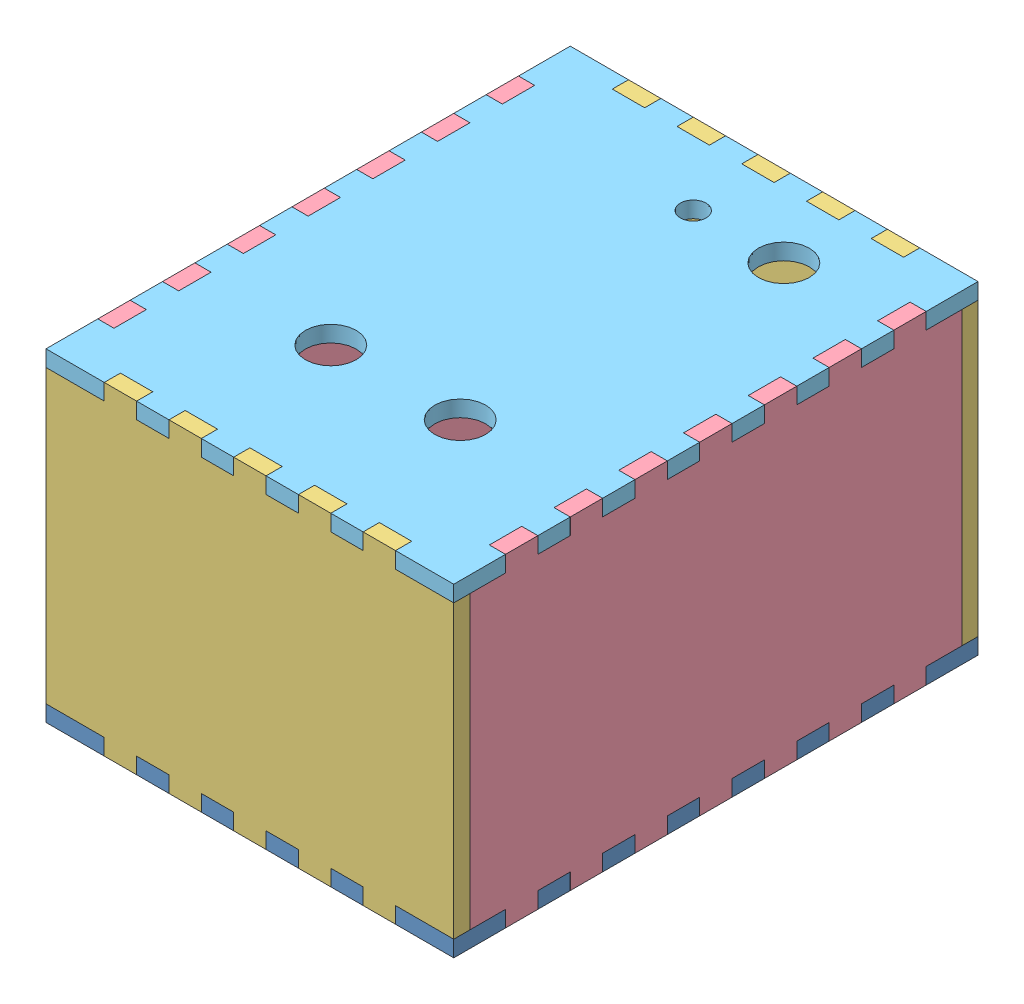
SolidWorks assembly ShellWithBreadboardAssy, configuration Default. Lengths in mm.
Overall size (80.01 63.5 102.87).
7 component instances, 5 part files, 18 mates.
Components (placement in the parent):
- ShellBottom-1: ShellBottom [Default] at (32.5711 51.104 75.4126) size (80.01 3.17 102.87)
- Breadboard-1: Breadboard [Default] at (32.5711 54.279 75.4126) x (0 0 1) z (-1 0 0) size (69 8.38 54)
- ShellShortSide-1: ShellShortSide [Default] at (32.5711 82.854 126.8476) x (0 0 -1) z (1 0 0) size (3.17 63.5 80.01)
- ShellShortSide-2: ShellShortSide [Battery cut-out] at (32.5711 82.854 27.1526) x (0 0 -1) z (1 0 0) size (3.17 63.5 80.01)
- ShellLongSide-1: ShellLongSide [Default] at (69.4011 82.854 75.4126) x (0 0 -1) z (1 0 0) size (96.52 63.5 3.17)
- ShellLongSide-2: ShellLongSide [Battery Mount Holes] at (-7.4339 82.854 75.4126) x (0 0 -1) z (1 0 0) size (96.52 63.5 3.17)
- ShellTop-1: ShellTop [Default] at (32.5711 111.429 75.4126) size (80.01 3.17 102.87)
Mates (geometry in assembly coordinates):
- Coincident1: coincident anti-aligned: plane of ShellBottom-1 through (32.5711 54.279 75.4126) normal (0 1 0); plane of Breadboard-1 through (32.5711 54.279 75.4126) normal (0 -1 0)
- Width1: width anti-aligned: plane of ShellBottom-1 through (-7.4339 54.279 126.8476) normal (0 0 1); plane of ShellBottom-1 through (-7.4339 54.279 23.9776) normal (0 0 -1); plane of Breadboard-1 through (59.5711 62.661 40.9126) normal (0 0 -1); plane of Breadboard-1 through (59.5711 62.661 109.9126) normal (0 0 1)
- Width2: width anti-aligned: plane of ShellBottom-1 through (72.5761 54.279 23.9776) normal (1 0 0); plane of ShellBottom-1 through (-7.4339 54.279 23.9776) normal (-1 0 0); plane of Breadboard-1 through (5.5711 62.661 40.9126) normal (-1 0 0); plane of Breadboard-1 through (59.5711 62.661 40.9126) normal (1 0 0)
- Coincident9: coincident aligned: plane of ShellBottom-1 through (32.5711 51.104 75.4126) normal (0 -1 0); plane of ShellShortSide-1 through (72.5761 51.104 123.6726) normal (0 -1 0)
- Coincident10: coincident aligned: plane of ShellBottom-1 through (72.5761 54.279 23.9776) normal (1 0 0); plane of ShellShortSide-1 through (72.5761 114.604 123.6726) normal (1 0 0)
- Coincident12: coincident aligned: plane of ShellBottom-1 through (32.5711 51.104 75.4126) normal (0 -1 0); plane of ShellShortSide-2 through (72.5761 51.104 23.9776) normal (0 -1 0)
- Coincident13: coincident aligned: plane of ShellBottom-1 through (-7.4339 54.279 23.9776) normal (-1 0 0); plane of ShellShortSide-2 through (-7.4339 114.604 23.9776) normal (-1 0 0)
- Coincident15: coincident aligned: plane of ShellBottom-1 through (32.5711 51.104 75.4126) normal (0 -1 0); plane of ShellLongSide-1 through (72.5761 51.104 123.6726) normal (0 -1 0)
- Coincident16: coincident anti-aligned: plane of ShellShortSide-1 through (32.5711 82.854 123.6726) normal (0 0 -1); plane of ShellLongSide-1 through (72.5761 114.604 123.6726) normal (0 0 1)
- Coincident18: coincident anti-aligned: plane of ShellShortSide-1 through (32.5711 82.854 123.6726) normal (0 0 -1); plane of ShellLongSide-2 through (-4.2589 114.604 123.6726) normal (0 0 1)
- Coincident19: coincident aligned: plane of ShellBottom-1 through (32.5711 51.104 75.4126) normal (0 -1 0); plane of ShellLongSide-2 through (-4.2589 51.104 123.6726) normal (0 -1 0)
- Coincident20: coincident anti-aligned: plane of ShellShortSide-2 through (61.1461 111.429 23.9776) normal (0 1 0); plane of ShellTop-1 through (32.5711 111.429 75.4126) normal (0 -1 0)
- Coincident21: coincident aligned: plane of ShellLongSide-1 through (72.5761 82.854 75.4126) normal (1 0 0); plane of ShellTop-1 through (72.5761 114.604 23.9776) normal (1 0 0)
- Coincident23: coincident aligned: plane of ShellBottom-1 through (-7.4339 54.279 23.9776) normal (-1 0 0); plane of ShellLongSide-2 through (-7.4339 82.854 75.4126) normal (-1 0 0)
- Coincident24: coincident aligned: plane of ShellBottom-1 through (72.5761 54.279 23.9776) normal (1 0 0); plane of ShellLongSide-1 through (72.5761 82.854 75.4126) normal (1 0 0)
- Coincident27: coincident anti-aligned: plane of ShellBottom-1 through (35.7461 51.104 123.6726) normal (0 0 1); plane of ShellShortSide-1 through (32.5711 82.854 123.6726) normal (0 0 -1)
- Coincident28: coincident anti-aligned: plane of ShellBottom-1 through (48.4461 51.104 27.1526) normal (0 0 -1); plane of ShellShortSide-2 through (32.5711 82.854 27.1526) normal (0 0 1)
- Coincident29: coincident anti-aligned: plane of ShellShortSide-1 through (32.5711 82.854 123.6726) normal (0 0 -1); plane of ShellTop-1 through (23.0461 111.429 123.6726) normal (0 0 1)
